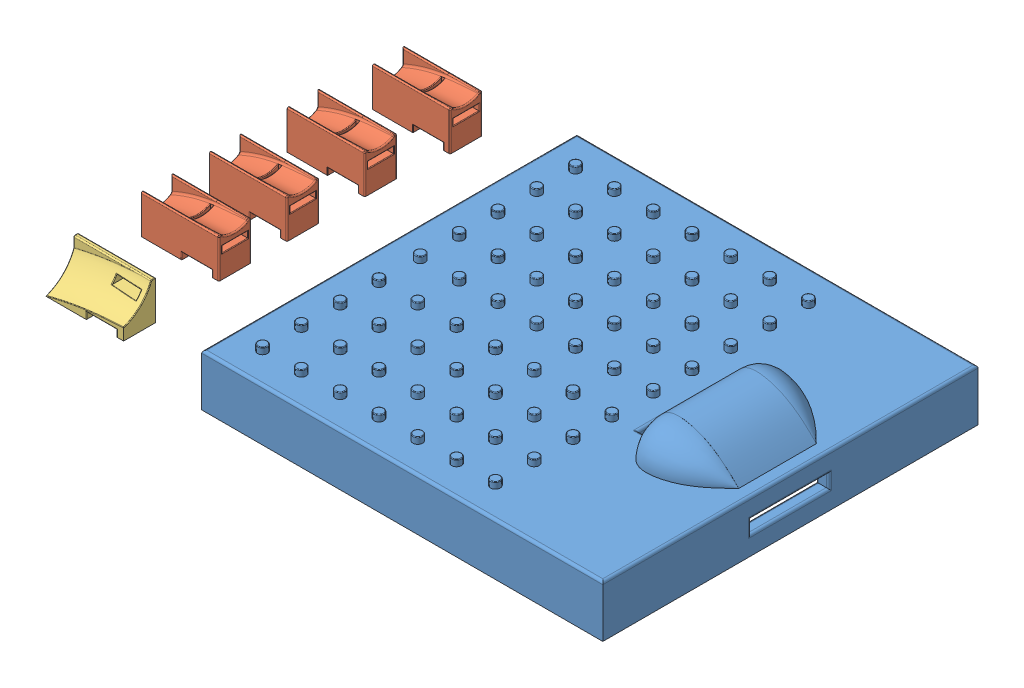
SolidWorks assembly hfs assembly, configuration Default. Lengths in mm.
Overall size (425.56 89.85 298.68).
6 component instances, 3 part files, 0 mates.
Components (placement in the parent):
- hfc part1 base-1: hfc part1 base [Default] at (135.759 227.1074 163.4788) size (310 69.21 290)
- hfc Part2 fingers-1: hfc Part2 fingers [Default] at (-69.9172 254.201 260.7621) size (60.87 32.3 25)
- hfc Part3 thumb-1: hfc Part3 thumb [Default] at (-99.7604 221.3081 304.6066) size (64.83 31.83 25.05)
- hfc Part2 fingers-2: hfc Part2 fingers [Default] at (-70.1237 254.3364 207.9911) size (60.87 32.3 25)
- hfc Part2 fingers-3: hfc Part2 fingers [Default] at (-70.0107 254.2623 147.9248) size (60.87 32.3 25)
- hfc Part2 fingers-4: hfc Part2 fingers [Default] at (-67.4037 252.5537 84.5856) size (60.87 32.3 25)
